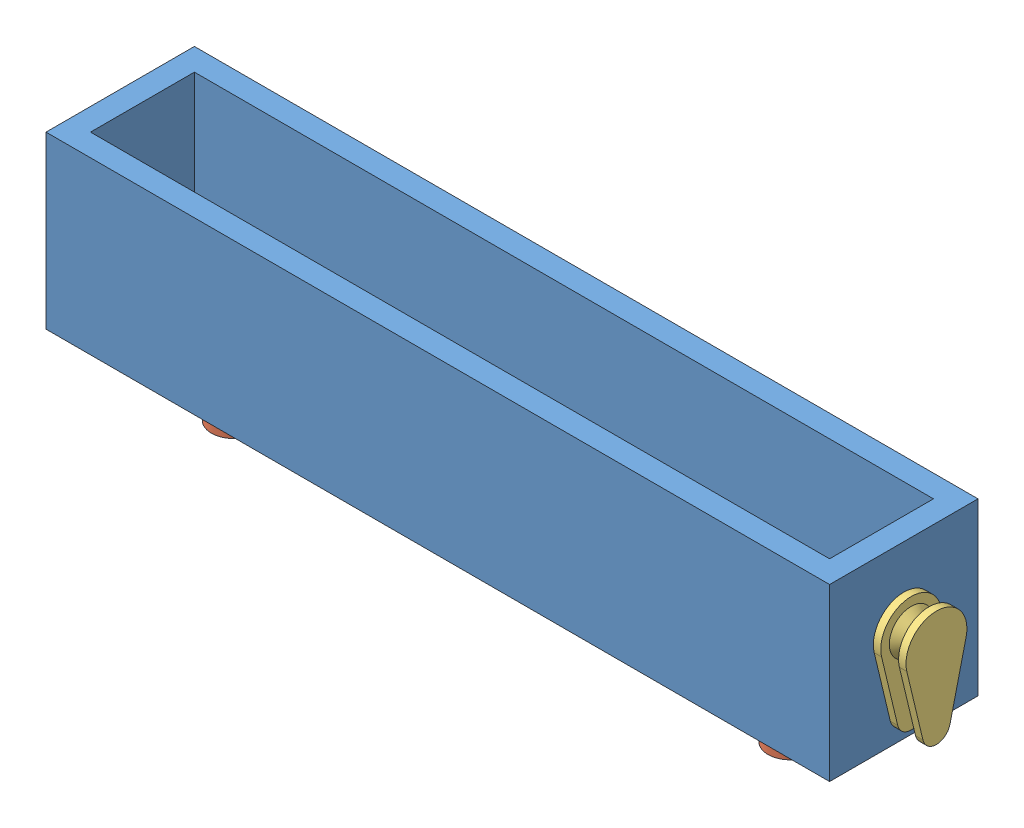
SolidWorks assembly 出绳点链接板（万向件）, configuration 默认. Lengths in mm.
Overall size (114.4 31 49).
5 component instances, 3 part files, 10 mates.
Components (placement in the parent):
- 出绳点链接板（100）-1: 出绳点链接板（100） [默认] at (-3.3008 48.9416 89.016) size (105.6 23 20)
- 柱塞螺丝M6-1: 柱塞螺丝M6 [默认] at (-40.8008 55.6816 89.016) x (-0.837169 0 -0.546944) z (-0.546944 0 0.837169) size (12 14.74 12)
- 柱塞螺丝M6-2: 柱塞螺丝M6 [默认] at (34.1992 55.6816 89.016) x (-0.837169 0 -0.546944) z (-0.546944 0 0.837169) size (12 14.74 12)
- 零件1^latest1-1: 零件1^latest1 [默认] at (-60.5008 197.9391 64.5018) x (0 0.000105 1) z (1 0 0) size (28.6 15.58 4.4)
- 零件1^latest1-2: 零件1^latest1 [默认] at (53.8992 197.9391 113.5302) x (0 0.000105 -1) z (-1 0 0) size (28.6 15.58 4.4)
Mates (geometry in assembly coordinates):
- 同心1: concentric anti-aligned: cylinder of 出绳点链接板（100）-1 through (-40.8008 51.9416 89.016) axis (0 -1 0) radius 4; cylinder of 柱塞螺丝M6-1 through (-40.8008 48.9416 89.016) axis (0 1 0) radius 4
- 重合1: coincident anti-aligned: plane of 出绳点链接板（100）-1 through (-3.3008 51.9416 89.016) normal (0 1 0); plane of 柱塞螺丝M6-1 through (-40.8008 51.9416 89.016) normal (0 -1 0)
- 同心2: concentric anti-aligned: cylinder of 出绳点链接板（100）-1 through (34.1992 51.9416 89.016) axis (0 -1 0) radius 4; cylinder of 柱塞螺丝M6-2 through (34.1992 48.9416 89.016) axis (0 1 0) radius 4
- 重合2: coincident anti-aligned: plane of 出绳点链接板（100）-1 through (-3.3008 51.9416 89.016) normal (0 1 0); plane of 柱塞螺丝M6-2 through (34.1992 51.9416 89.016) normal (0 -1 0)
- 重合3: coincident anti-aligned: plane of 出绳点链接板（100）-1 through (49.4992 51.9416 89.016) normal (1 0 0); plane of 零件1^latest1-2 through (49.4992 61.9416 89.016) normal (-1 0 0)
- 同心3: concentric aligned: cylinder of 出绳点链接板（100）-1 through (53.8992 61.9416 89.016) axis (-1 0 0) radius 2; cylinder of 零件1^latest1-2 through (49.6992 61.9416 89.016) axis (-1 0 0) radius 1.5294
- 平行1: parallel anti-aligned: line of 出绳点链接板（100）-1 through (49.4992 71.9416 79.016) axis (0 -1 0); line of 零件1^latest1-2 through (51.6992 50.4649 89.0164) axis (0 1 0)
- 重合5: coincident anti-aligned: plane of 出绳点链接板（100）-1 through (-56.1008 51.9416 89.016) normal (-1 0 0); plane of 零件1^latest1-1 through (-56.1008 61.9416 89.016) normal (1 0 0)
- 同心4: concentric anti-aligned: cylinder of 出绳点链接板（100）-1 through (53.8992 61.9416 89.016) axis (-1 0 0) radius 2; cylinder of 零件1^latest1-1 through (-56.3008 61.9416 89.016) axis (1 0 0) radius 1.5294
- 平行2: parallel anti-aligned: line of 出绳点链接板（100）-1 through (-56.1008 71.9416 79.016) axis (0 -1 0); line of 零件1^latest1-1 through (-58.3008 50.4649 89.0156) axis (0 1 0)
